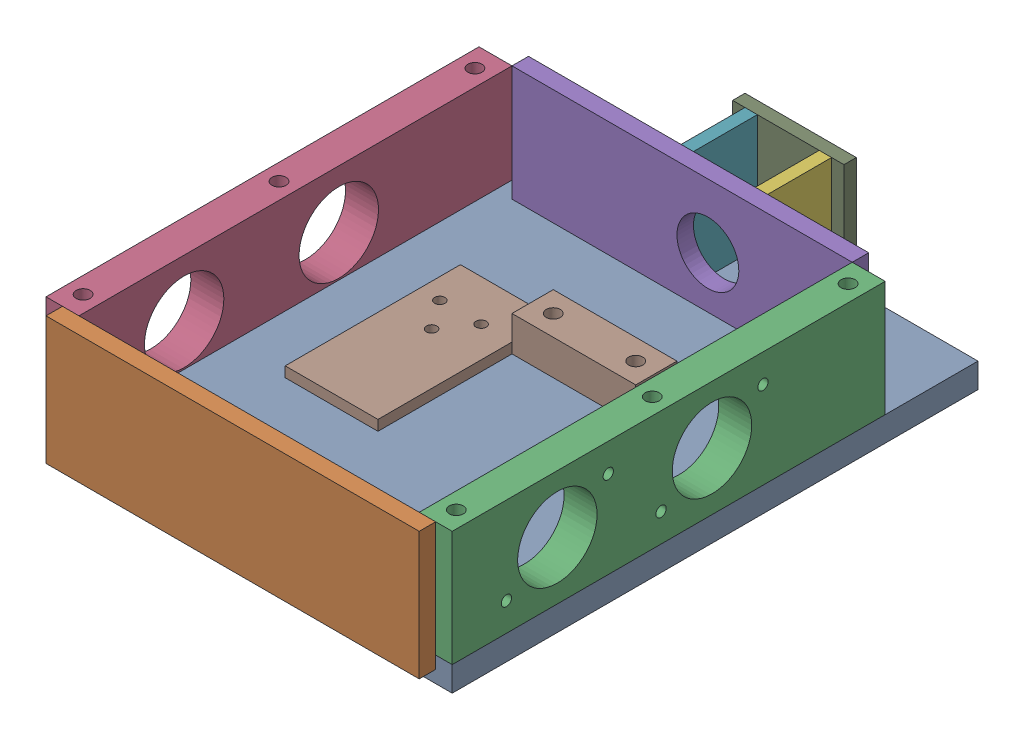
SolidWorks assembly g1_3_1_1_8_1_af0_1, configuration 默认. Lengths in mm.
Overall size (197 68 263).
9 component instances, 8 part files, 0 mates.
Components (placement in the parent):
- g1_3_1_1_8_1-3_af1_1-1: g1_3_1_1_8_1-3_af1_1 [默认] at origin size (197 12 255)
- g1_3_1_1_8_1-1_1-1: g1_3_1_1_8_1-1_1 [默认] at (0 37 127.5) x (1 0 0) z (0 -1 0) size (181 8 62)
- g1_3_1_1_8_1-2_af1_1-1: g1_3_1_1_8_1-2_af1_1 [默认] at (98.5 40 22.5) x (0 1 0) z (0 0 1) size (56 16 210)
- g1_3_1_1_8_1-2_af0_1-1: g1_3_1_1_8_1-2_af0_1 [默认] at (-98.5 40 22.5) x (0 1 0) z (0 0 -1) size (56 16 210)
- g1_3_1_1_8_1-5_1-1: g1_3_1_1_8_1-5_1 [默认] at (0 40 -82.5) x (1 0 0) z (0 1 0) size (165 8 56)
- g1_3_1_1_8_1-6_1-1: g1_3_1_1_8_1-6_1 [默认] at (27.5 40 -106) x (0 1 0) z (0 0 -1) size (56 6 31)
- g1_3_1_1_8_1-6_1-2: g1_3_1_1_8_1-6_1 [默认] at (-8.5 40 -106) x (0 1 0) z (0 0 -1) size (56 6 31)
- g1_3_1_1_8_1-4_af1_1-1: g1_3_1_1_8_1-4_af1_1 [默认] at (-10 12 5) size (105 17 85)
- g1_3_1_1_8_1-8_af0_1-1: g1_3_1_1_8_1-8_af0_1 [默认] at (12.5 40 -127.5) x (0 1 0) z (1 0 0) size (56 6 54)
